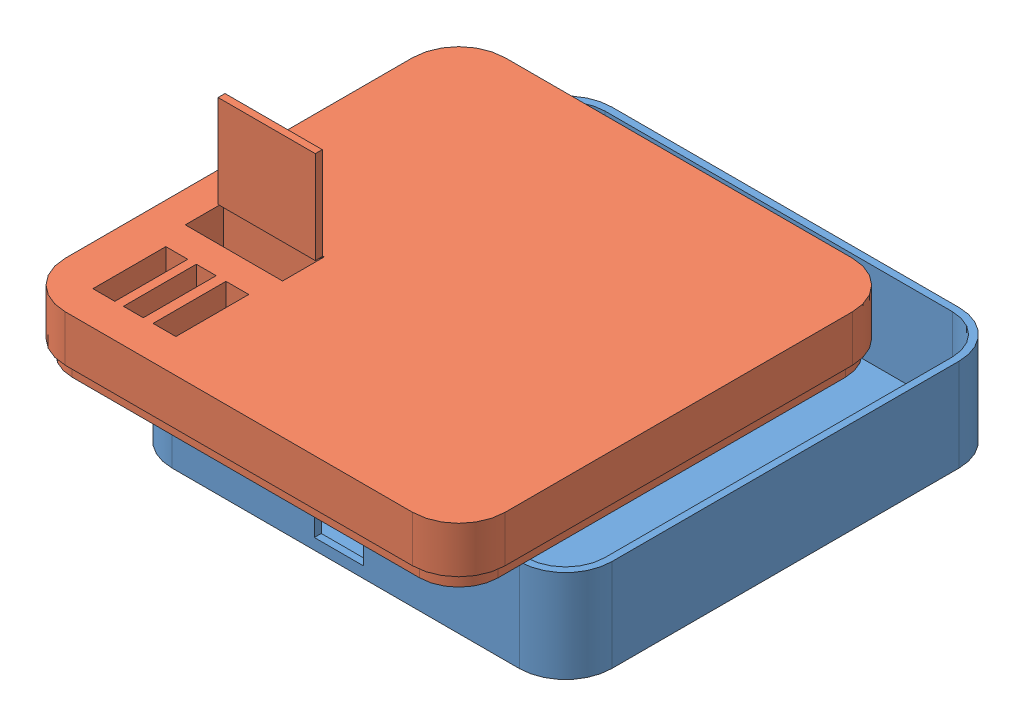
SolidWorks assembly Assem2, configuration Default. Lengths in mm.
Overall size (144.16 86.7 144).
2 component instances, 2 part files, 0 mates.
Components (placement in the parent):
- Part1-1: Part1 [Default] at (38.273 24.6186 81.5987) size (95 20 95)
- Part5-1: Part5 [Default] at (109.4722 81.3184 136.1974) size (118.2 33 95)
